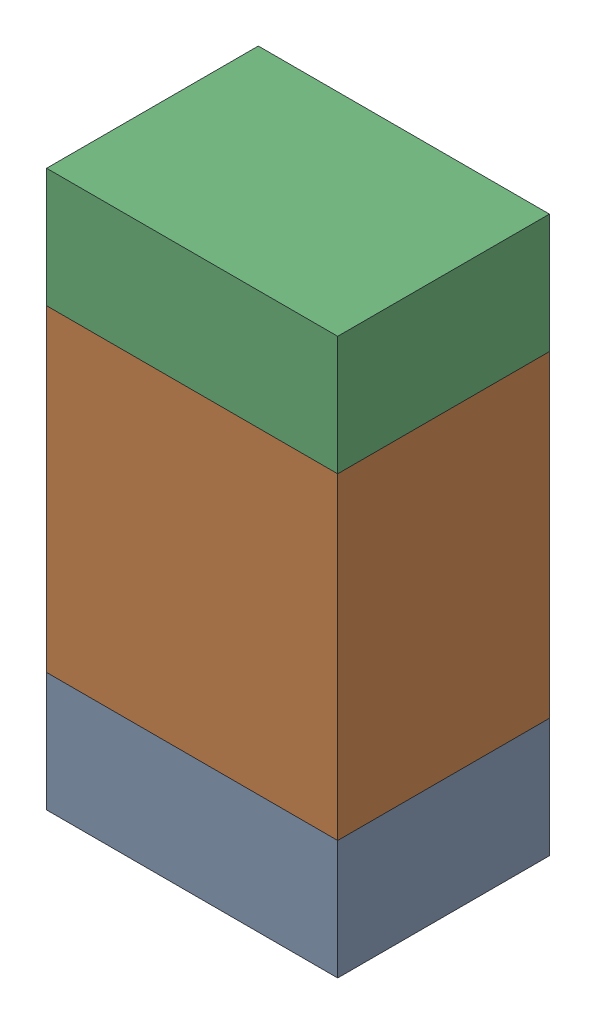
SolidWorks assembly R309_1PCB, configuration Default. Lengths in mm.
Overall size (0.55 1.05 0.4).
6 component instances, 2 part files, 0 mates.
Components (placement in the parent):
- 846483288-1: 846483288 [Default] at (133.3501 107.7217 -2.0638) size (0.55 0.22 0.4)
  - Extruded_12-1: Extruded_12 [Default] at origin size (0.55 0.22 0.4)
- 846483424-1: 846483424 [Default] at (133.3501 108.1342 -2.0638) size (0.55 0.6 0.4)
  - Extruded_13-1: Extruded_13 [Default] at origin size (0.55 0.6 0.4)
- 846483288-2: 846483288 [Default] at (133.3501 108.5467 -2.0638) size (0.55 0.22 0.4)
  - Extruded_12-1: Extruded_12 [Default] at origin size (0.55 0.22 0.4)
